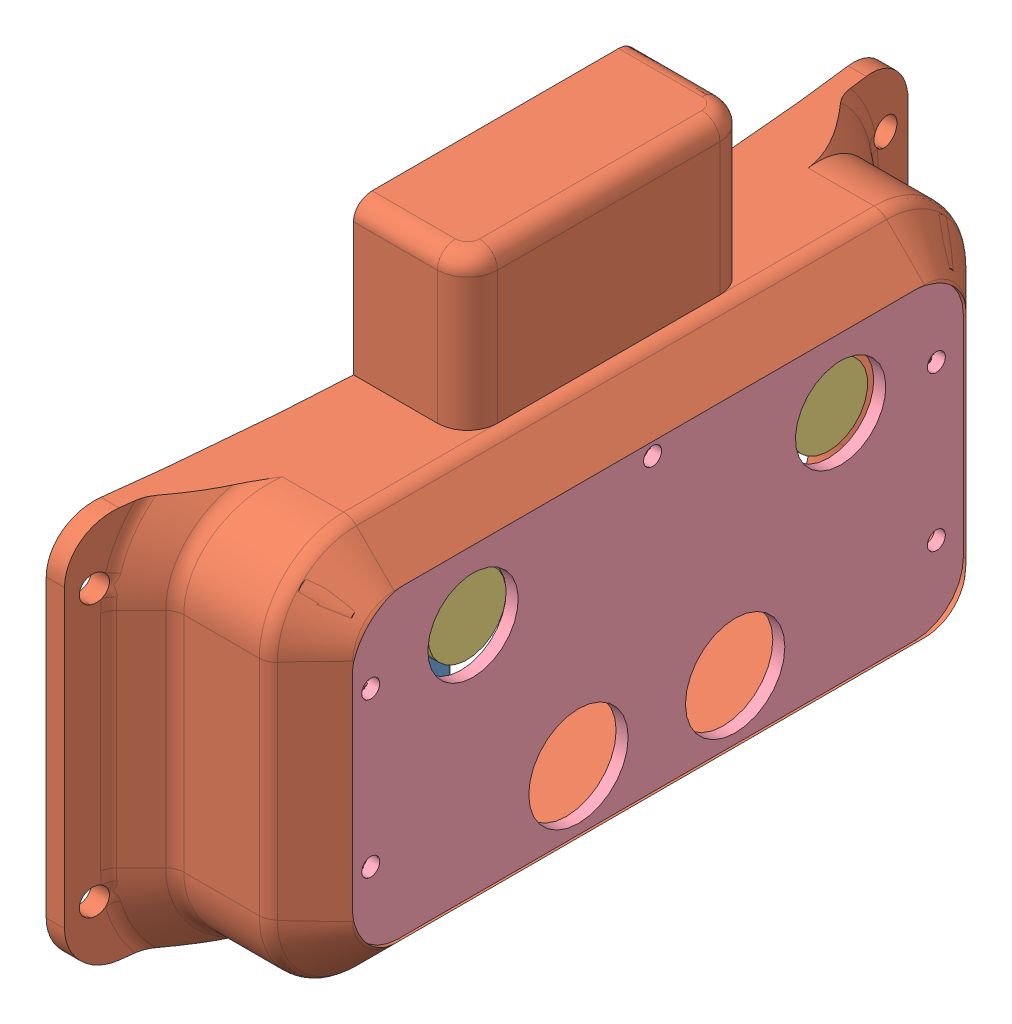
SolidWorks assembly 视觉套装装配, configuration 默认. Lengths in mm.
Overall size (33 90 140).
4 component instances, 4 part files, 3 mates.
Components (placement in the parent):
- 机器人头部传感器v2-1: 机器人头部传感器v2 [Default] at (-15.2633 11.9346 169.7675) size (9.94 55 110)
- 摄像头保护罩-1: 摄像头保护罩 [默认] at (-42.6373 26.8239 118.905) x (-1 0 0) z (0 0 1) size (33 90 140)
- 摄像头-1: 摄像头 [默认] at (-13.3029 -3.9021 109.3952) x (0 0 -1) z (1 0 0) size (80 27.2 16)
- 传感器挡板-1: 传感器挡板 [默认] at (2.6971 -11.6096 102.6877) x (0 0 1) z (0 1 0) size (101.76 2 50.76)
Mates (geometry in assembly coordinates):
- 重合1: coincident anti-aligned: plane of 机器人头部传感器v2-1 through (-13.3029 21.9346 169.7675) normal (1 0 0); plane of 摄像头-1 through (-13.3029 -3.9021 109.3952) normal (-1 0 0)
- 平行4: parallel aligned: plane of 机器人头部传感器v2-1 through (-15.2633 21.9346 169.7675) normal (0 1 0); plane of 摄像头保护罩-1 through (-42.6373 26.8239 118.905) normal (0 1 0)
- 同心10: concentric aligned: cylinder of 摄像头-1 through (2.6971 7.8239 79.3952) axis (-1 0 0) radius 6.5; cylinder of 传感器挡板-1 through (4.6971 7.8239 79.3952) axis (-1 0 0) radius 7.5
